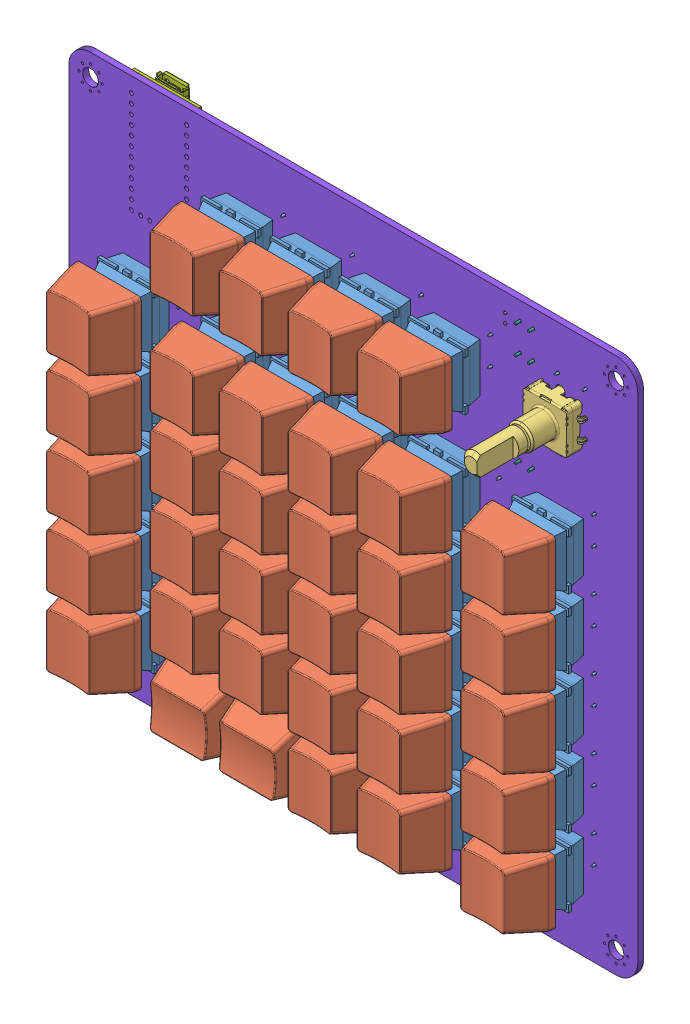
SolidWorks assembly OsseyPad, configuration Default. Lengths in mm.
Overall size (157 148.99 30.28).
224 component instances, 8 part files, 0 mates.
Components (placement in the parent):
- OsseyPad.step-1: OsseyPad.step [Default] at origin size (157 148.99 30.28)
  - mx.step-1: mx.step [Default] at (130.9688 -95.25 7.25) x (-1 0 0) z (0 1 0) size (15.64 22.93 22.24)
    - SOLID.step-1: SOLID.step [Default] at origin size (15.64 22.93 22.24)
  - mxKeycap.step-1: mxKeycap.step [Default] at (121.9688 -86.25 11.95) x (1 0 0) z (0 -1 0) size (18 11.3 18.01)
    - SOLID-0.step-1: SOLID-0.step [Default] at origin size (18 11.3 18.01)
  - mx.step-2: mx.step [Default] at (150.0188 -95.25 7.25) x (-1 0 0) z (0 1 0) size (15.64 22.93 22.24)
    - SOLID.step-1: SOLID.step [Default] at origin size (15.64 22.93 22.24)
  - mxKeycap.step-2: mxKeycap.step [Default] at (141.0188 -86.25 11.95) x (1 0 0) z (0 -1 0) size (18 11.3 18.01)
    - SOLID-0.step-1: SOLID-0.step [Default] at origin size (18 11.3 18.01)
  - mx.step-3: mx.step [Default] at (169.0687 -95.25 7.25) x (-1 0 0) z (0 1 0) size (15.64 22.93 22.24)
    - SOLID.step-1: SOLID.step [Default] at origin size (15.64 22.93 22.24)
  - mxKeycap.step-3: mxKeycap.step [Default] at (160.0688 -86.25 11.95) x (1 0 0) z (0 -1 0) size (18 11.3 18.01)
    - SOLID-0.step-1: SOLID-0.step [Default] at origin size (18 11.3 18.01)
  - mx.step-4: mx.step [Default] at (188.1188 -95.25 7.25) x (-1 0 0) z (0 1 0) size (15.64 22.93 22.24)
    - SOLID.step-1: SOLID.step [Default] at origin size (15.64 22.93 22.24)
  - mxKeycap.step-4: mxKeycap.step [Default] at (179.1188 -86.25 11.95) x (1 0 0) z (0 -1 0) size (18 11.3 18.01)
    - SOLID-0.step-1: SOLID-0.step [Default] at origin size (18 11.3 18.01)
  - mx.step-5: mx.step [Default] at (102.3938 -123.825 7.25) x (-1 0 0) z (0 1 0) size (15.64 22.93 22.24)
    - SOLID.step-1: SOLID.step [Default] at origin size (15.64 22.93 22.24)
  - mxKeycap.step-5: mxKeycap.step [Default] at (93.3937 -114.825 11.95) x (1 0 0) z (0 -1 0) size (18 11.3 18.01)
    - SOLID-0.step-1: SOLID-0.step [Default] at origin size (18 11.3 18.01)
  - mx.step-6: mx.step [Default] at (130.9688 -123.825 7.25) x (-1 0 0) z (0 1 0) size (15.64 22.93 22.24)
    - SOLID.step-1: SOLID.step [Default] at origin size (15.64 22.93 22.24)
  - mxKeycap.step-6: mxKeycap.step [Default] at (121.9688 -114.825 11.95) x (1 0 0) z (0 -1 0) size (18 11.3 18.01)
    - SOLID-0.step-1: SOLID-0.step [Default] at origin size (18 11.3 18.01)
  - mx.step-7: mx.step [Default] at (150.0188 -123.825 7.25) x (-1 0 0) z (0 1 0) size (15.64 22.93 22.24)
    - SOLID.step-1: SOLID.step [Default] at origin size (15.64 22.93 22.24)
  - mxKeycap.step-7: mxKeycap.step [Default] at (141.0188 -114.825 11.95) x (1 0 0) z (0 -1 0) size (18 11.3 18.01)
    - SOLID-0.step-1: SOLID-0.step [Default] at origin size (18 11.3 18.01)
  - mx.step-8: mx.step [Default] at (169.0687 -123.825 7.25) x (-1 0 0) z (0 1 0) size (15.64 22.93 22.24)
    - SOLID.step-1: SOLID.step [Default] at origin size (15.64 22.93 22.24)
  - mxKeycap.step-8: mxKeycap.step [Default] at (160.0688 -114.825 11.95) x (1 0 0) z (0 -1 0) size (18 11.3 18.01)
    - SOLID-0.step-1: SOLID-0.step [Default] at origin size (18 11.3 18.01)
  - mx.step-9: mx.step [Default] at (188.1188 -123.825 7.25) x (-1 0 0) z (0 1 0) size (15.64 22.93 22.24)
    - SOLID.step-1: SOLID.step [Default] at origin size (15.64 22.93 22.24)
  - mxKeycap.step-9: mxKeycap.step [Default] at (179.1188 -114.825 11.95) x (1 0 0) z (0 -1 0) size (18 11.3 18.01)
    - SOLID-0.step-1: SOLID-0.step [Default] at origin size (18 11.3 18.01)
  - mx.step-10: mx.step [Default] at (216.6937 -123.825 7.25) x (-1 0 0) z (0 1 0) size (15.64 22.93 22.24)
    - SOLID.step-1: SOLID.step [Default] at origin size (15.64 22.93 22.24)
  - mxKeycap.step-10: mxKeycap.step [Default] at (207.6938 -114.825 11.95) x (1 0 0) z (0 -1 0) size (18 11.3 18.01)
    - SOLID-0.step-1: SOLID-0.step [Default] at origin size (18 11.3 18.01)
  - mx.step-11: mx.step [Default] at (102.3938 -142.875 7.25) x (-1 0 0) z (0 1 0) size (15.64 22.93 22.24)
    - SOLID.step-1: SOLID.step [Default] at origin size (15.64 22.93 22.24)
  - mxKeycap.step-11: mxKeycap.step [Default] at (93.3937 -133.875 11.95) x (1 0 0) z (0 -1 0) size (18 11.3 18.01)
    - SOLID-0.step-1: SOLID-0.step [Default] at origin size (18 11.3 18.01)
  - mx.step-12: mx.step [Default] at (130.9688 -142.875 7.25) x (-1 0 0) z (0 1 0) size (15.64 22.93 22.24)
    - SOLID.step-1: SOLID.step [Default] at origin size (15.64 22.93 22.24)
  - mxKeycap.step-12: mxKeycap.step [Default] at (121.9688 -133.875 11.95) x (1 0 0) z (0 -1 0) size (18 11.3 18.01)
    - SOLID-0.step-1: SOLID-0.step [Default] at origin size (18 11.3 18.01)
  - mx.step-13: mx.step [Default] at (150.0188 -142.875 7.25) x (-1 0 0) z (0 1 0) size (15.64 22.93 22.24)
    - SOLID.step-1: SOLID.step [Default] at origin size (15.64 22.93 22.24)
  - mxKeycap.step-13: mxKeycap.step [Default] at (141.0188 -133.875 11.95) x (1 0 0) z (0 -1 0) size (18 11.3 18.01)
    - SOLID-0.step-1: SOLID-0.step [Default] at origin size (18 11.3 18.01)
  - mx.step-14: mx.step [Default] at (169.0687 -142.875 7.25) x (-1 0 0) z (0 1 0) size (15.64 22.93 22.24)
    - SOLID.step-1: SOLID.step [Default] at origin size (15.64 22.93 22.24)
  - mxKeycap.step-14: mxKeycap.step [Default] at (160.0688 -133.875 11.95) x (1 0 0) z (0 -1 0) size (18 11.3 18.01)
    - SOLID-0.step-1: SOLID-0.step [Default] at origin size (18 11.3 18.01)
  - mx.step-15: mx.step [Default] at (188.1188 -142.875 7.25) x (-1 0 0) z (0 1 0) size (15.64 22.93 22.24)
    - SOLID.step-1: SOLID.step [Default] at origin size (15.64 22.93 22.24)
  - mxKeycap.step-15: mxKeycap.step [Default] at (179.1188 -133.875 11.95) x (1 0 0) z (0 -1 0) size (18 11.3 18.01)
    - SOLID-0.step-1: SOLID-0.step [Default] at origin size (18 11.3 18.01)
  - mx.step-16: mx.step [Default] at (216.6937 -142.875 7.25) x (-1 0 0) z (0 1 0) size (15.64 22.93 22.24)
    - SOLID.step-1: SOLID.step [Default] at origin size (15.64 22.93 22.24)
  - mxKeycap.step-16: mxKeycap.step [Default] at (207.6938 -133.875 11.95) x (1 0 0) z (0 -1 0) size (18 11.3 18.01)
    - SOLID-0.step-1: SOLID-0.step [Default] at origin size (18 11.3 18.01)
  - mx.step-17: mx.step [Default] at (102.3938 -161.925 7.25) x (-1 0 0) z (0 1 0) size (15.64 22.93 22.24)
    - SOLID.step-1: SOLID.step [Default] at origin size (15.64 22.93 22.24)
  - mxKeycap.step-17: mxKeycap.step [Default] at (93.3937 -152.925 11.95) x (1 0 0) z (0 -1 0) size (18 11.3 18.01)
    - SOLID-0.step-1: SOLID-0.step [Default] at origin size (18 11.3 18.01)
  - mx.step-18: mx.step [Default] at (130.9688 -161.925 7.25) x (-1 0 0) z (0 1 0) size (15.64 22.93 22.24)
    - SOLID.step-1: SOLID.step [Default] at origin size (15.64 22.93 22.24)
  - mxKeycap.step-18: mxKeycap.step [Default] at (121.9688 -152.925 11.95) x (1 0 0) z (0 -1 0) size (18 11.3 18.01)
    - SOLID-0.step-1: SOLID-0.step [Default] at origin size (18 11.3 18.01)
  - mx.step-19: mx.step [Default] at (150.0188 -161.925 7.25) x (-1 0 0) z (0 1 0) size (15.64 22.93 22.24)
    - SOLID.step-1: SOLID.step [Default] at origin size (15.64 22.93 22.24)
  - mxKeycap.step-19: mxKeycap.step [Default] at (141.0188 -152.925 11.95) x (1 0 0) z (0 -1 0) size (18 11.3 18.01)
    - SOLID-0.step-1: SOLID-0.step [Default] at origin size (18 11.3 18.01)
  - mx.step-20: mx.step [Default] at (169.0687 -161.925 7.25) x (-1 0 0) z (0 1 0) size (15.64 22.93 22.24)
    - SOLID.step-1: SOLID.step [Default] at origin size (15.64 22.93 22.24)
  - mxKeycap.step-20: mxKeycap.step [Default] at (160.0688 -152.925 11.95) x (1 0 0) z (0 -1 0) size (18 11.3 18.01)
    - SOLID-0.step-1: SOLID-0.step [Default] at origin size (18 11.3 18.01)
  - mx.step-21: mx.step [Default] at (188.1188 -161.925 7.25) x (-1 0 0) z (0 1 0) size (15.64 22.93 22.24)
    - SOLID.step-1: SOLID.step [Default] at origin size (15.64 22.93 22.24)
  - mxKeycap.step-21: mxKeycap.step [Default] at (179.1188 -152.925 11.95) x (1 0 0) z (0 -1 0) size (18 11.3 18.01)
    - SOLID-0.step-1: SOLID-0.step [Default] at origin size (18 11.3 18.01)
  - mx.step-22: mx.step [Default] at (216.6937 -161.925 7.25) x (-1 0 0) z (0 1 0) size (15.64 22.93 22.24)
    - SOLID.step-1: SOLID.step [Default] at origin size (15.64 22.93 22.24)
  - mxKeycap.step-22: mxKeycap.step [Default] at (207.6938 -152.925 11.95) x (1 0 0) z (0 -1 0) size (18 11.3 18.01)
    - SOLID-0.step-1: SOLID-0.step [Default] at origin size (18 11.3 18.01)
  - mx.step-23: mx.step [Default] at (188.1188 -180.975 7.25) x (-1 0 0) z (0 1 0) size (15.64 22.93 22.24)
    - SOLID.step-1: SOLID.step [Default] at origin size (15.64 22.93 22.24)
  - mxKeycap.step-23: mxKeycap.step [Default] at (179.1188 -171.975 11.95) x (1 0 0) z (0 -1 0) size (18 11.3 18.01)
    - SOLID-0.step-1: SOLID-0.step [Default] at origin size (18 11.3 18.01)
  - mx.step-24: mx.step [Default] at (102.3938 -180.975 7.25) x (-1 0 0) z (0 1 0) size (15.64 22.93 22.24)
    - SOLID.step-1: SOLID.step [Default] at origin size (15.64 22.93 22.24)
  - mxKeycap.step-24: mxKeycap.step [Default] at (93.3937 -171.975 11.95) x (1 0 0) z (0 -1 0) size (18 11.3 18.01)
    - SOLID-0.step-1: SOLID-0.step [Default] at origin size (18 11.3 18.01)
  - mx.step-25: mx.step [Default] at (130.9688 -180.975 7.25) x (-1 0 0) z (0 1 0) size (15.64 22.93 22.24)
    - SOLID.step-1: SOLID.step [Default] at origin size (15.64 22.93 22.24)
  - mxKeycap.step-25: mxKeycap.step [Default] at (121.9688 -171.975 11.95) x (1 0 0) z (0 -1 0) size (18 11.3 18.01)
    - SOLID-0.step-1: SOLID-0.step [Default] at origin size (18 11.3 18.01)
  - mx.step-26: mx.step [Default] at (150.0188 -180.975 7.25) x (-1 0 0) z (0 1 0) size (15.64 22.93 22.24)
    - SOLID.step-1: SOLID.step [Default] at origin size (15.64 22.93 22.24)
  - mxKeycap.step-26: mxKeycap.step [Default] at (141.0188 -171.975 11.95) x (1 0 0) z (0 -1 0) size (18 11.3 18.01)
    - SOLID-0.step-1: SOLID-0.step [Default] at origin size (18 11.3 18.01)
  - mx.step-27: mx.step [Default] at (169.0687 -180.975 7.25) x (-1 0 0) z (0 1 0) size (15.64 22.93 22.24)
    - SOLID.step-1: SOLID.step [Default] at origin size (15.64 22.93 22.24)
  - mxKeycap.step-27: mxKeycap.step [Default] at (160.0688 -171.975 11.95) x (1 0 0) z (0 -1 0) size (18 11.3 18.01)
    - SOLID-0.step-1: SOLID-0.step [Default] at origin size (18 11.3 18.01)
  - mx.step-28: mx.step [Default] at (216.6937 -180.975 7.25) x (-1 0 0) z (0 1 0) size (15.64 22.93 22.24)
    - SOLID.step-1: SOLID.step [Default] at origin size (15.64 22.93 22.24)
  - mxKeycap.step-28: mxKeycap.step [Default] at (207.6938 -171.975 11.95) x (1 0 0) z (0 -1 0) size (18 11.3 18.01)
    - SOLID-0.step-1: SOLID-0.step [Default] at origin size (18 11.3 18.01)
  - mx.step-29: mx.step [Default] at (102.3938 -200.025 7.25) x (-1 0 0) z (0 1 0) size (15.64 22.93 22.24)
    - SOLID.step-1: SOLID.step [Default] at origin size (15.64 22.93 22.24)
  - mxKeycap.step-29: mxKeycap.step [Default] at (93.3937 -191.025 11.95) x (1 0 0) z (0 -1 0) size (18 11.3 18.01)
    - SOLID-0.step-1: SOLID-0.step [Default] at origin size (18 11.3 18.01)
  - mx.step-30: mx.step [Default] at (130.9688 -200.025 7.25) x (0 1 0) z (1 0 0) size (15.64 22.93 22.24)
    - SOLID.step-1: SOLID.step [Default] at origin size (15.64 22.93 22.24)
  - mxKeycap.step-30: mxKeycap.step [Default] at (139.9688 -191.025 11.95) x (0 -1 0) z (-1 0 0) size (18 11.3 18.01)
    - SOLID-0.step-1: SOLID-0.step [Default] at origin size (18 11.3 18.01)
  - mx.step-31: mx.step [Default] at (150.0188 -200.025 7.25) x (0 1 0) z (1 0 0) size (15.64 22.93 22.24)
    - SOLID.step-1: SOLID.step [Default] at origin size (15.64 22.93 22.24)
  - mxKeycap.step-31: mxKeycap.step [Default] at (159.0187 -191.025 11.95) x (0 -1 0) z (-1 0 0) size (18 11.3 18.01)
    - SOLID-0.step-1: SOLID-0.step [Default] at origin size (18 11.3 18.01)
  - mx.step-32: mx.step [Default] at (169.0687 -200.025 7.25) x (-1 0 0) z (0 1 0) size (15.64 22.93 22.24)
    - SOLID.step-1: SOLID.step [Default] at origin size (15.64 22.93 22.24)
  - mxKeycap.step-32: mxKeycap.step [Default] at (160.0688 -191.025 11.95) x (1 0 0) z (0 -1 0) size (18 11.3 18.01)
    - SOLID-0.step-1: SOLID-0.step [Default] at origin size (18 11.3 18.01)
  - mx.step-33: mx.step [Default] at (188.1188 -200.025 7.25) x (-1 0 0) z (0 1 0) size (15.64 22.93 22.24)
    - SOLID.step-1: SOLID.step [Default] at origin size (15.64 22.93 22.24)
  - mxKeycap.step-33: mxKeycap.step [Default] at (179.1188 -191.025 11.95) x (1 0 0) z (0 -1 0) size (18 11.3 18.01)
    - SOLID-0.step-1: SOLID-0.step [Default] at origin size (18 11.3 18.01)
  - mx.step-34: mx.step [Default] at (216.6937 -200.025 7.25) x (-1 0 0) z (0 1 0) size (15.64 22.93 22.24)
    - SOLID.step-1: SOLID.step [Default] at origin size (15.64 22.93 22.24)
  - mxKeycap.step-34: mxKeycap.step [Default] at (207.6938 -191.025 11.95) x (1 0 0) z (0 -1 0) size (18 11.3 18.01)
    - SOLID-0.step-1: SOLID-0.step [Default] at origin size (18 11.3 18.01)
  - EC11E-05SW.step-1: EC11E-05SW.step [Default] at (216.6937 -95 -10.35) x (0 1 0) z (0 0 -1) size (13.28 15.04 28.35)
    - SOLID-1.step-1: SOLID-1.step [Default] at origin size (13.28 15.04 28.35)
  - C_Disc_D3.0mm_W2.0mm_P2.50mm.step-1: C_Disc_D3.0mm_W2.0mm_P2.50mm.step [Default] at (201.53 -111.84 -0.05) x (0 1 0) z (0 0 -1) size (3.35 3.34 5.33)
    - SOLID-2.step-1: SOLID-2.step [Default] at origin size (3.35 3.34 5.33)
  - C_Disc_D3.0mm_W2.0mm_P2.50mm.step-2: C_Disc_D3.0mm_W2.0mm_P2.50mm.step [Default] at (201.53 -78.63 -0.05) x (0 -1 0) z (0 0 -1) size (3.35 3.34 5.33)
    - SOLID-2.step-1: SOLID-2.step [Default] at origin size (3.35 3.34 5.33)
  - D_DO-35_SOD27_P7.62mm_Horizontal.step-1: D_DO-35_SOD27_P7.62mm_Horizontal.step [Default] at (140.4938 -85.725 -0.05) x (0 -1 0) z (0 0 -1) size (8.12 2.93 5.28)
    - COMPOUND.step-1: COMPOUND.step [Default] at origin size (8.12 2.93 5.28)
  - D_DO-35_SOD27_P7.62mm_Horizontal.step-2: D_DO-35_SOD27_P7.62mm_Horizontal.step [Default] at (159.5438 -85.725 -0.05) x (0 -1 0) z (0 0 -1) size (8.12 2.93 5.28)
    - COMPOUND.step-1: COMPOUND.step [Default] at origin size (8.12 2.93 5.28)
  - D_DO-35_SOD27_P7.62mm_Horizontal.step-3: D_DO-35_SOD27_P7.62mm_Horizontal.step [Default] at (178.5938 -85.725 -0.05) x (0 -1 0) z (0 0 -1) size (8.12 2.93 5.28)
    - COMPOUND.step-1: COMPOUND.step [Default] at origin size (8.12 2.93 5.28)
  - D_DO-35_SOD27_P7.62mm_Horizontal.step-4: D_DO-35_SOD27_P7.62mm_Horizontal.step [Default] at (197.6438 -85.725 -0.05) x (0 -1 0) z (0 0 -1) size (8.12 2.93 5.28)
    - COMPOUND.step-1: COMPOUND.step [Default] at origin size (8.12 2.93 5.28)
  - D_DO-35_SOD27_P7.62mm_Horizontal.step-5: D_DO-35_SOD27_P7.62mm_Horizontal.step [Default] at (216.07 -85.725 -0.05) x (1 0 0) z (0 0 -1) size (8.12 2.93 5.28)
    - COMPOUND.step-1: COMPOUND.step [Default] at origin size (8.12 2.93 5.28)
  - D_DO-35_SOD27_P7.62mm_Horizontal.step-6: D_DO-35_SOD27_P7.62mm_Horizontal.step [Default] at (111.9188 -114.3 -0.05) x (0 -1 0) z (0 0 -1) size (8.12 2.93 5.28)
    - COMPOUND.step-1: COMPOUND.step [Default] at origin size (8.12 2.93 5.28)
  - D_DO-35_SOD27_P7.62mm_Horizontal.step-7: D_DO-35_SOD27_P7.62mm_Horizontal.step [Default] at (140.4938 -114.3 -0.05) x (0 -1 0) z (0 0 -1) size (8.12 2.93 5.28)
    - COMPOUND.step-1: COMPOUND.step [Default] at origin size (8.12 2.93 5.28)
  - D_DO-35_SOD27_P7.62mm_Horizontal.step-8: D_DO-35_SOD27_P7.62mm_Horizontal.step [Default] at (159.5438 -114.3 -0.05) x (0 -1 0) z (0 0 -1) size (8.12 2.93 5.28)
    - COMPOUND.step-1: COMPOUND.step [Default] at origin size (8.12 2.93 5.28)
  - D_DO-35_SOD27_P7.62mm_Horizontal.step-9: D_DO-35_SOD27_P7.62mm_Horizontal.step [Default] at (178.5938 -114.3 -0.05) x (0 -1 0) z (0 0 -1) size (8.12 2.93 5.28)
    - COMPOUND.step-1: COMPOUND.step [Default] at origin size (8.12 2.93 5.28)
  - D_DO-35_SOD27_P7.62mm_Horizontal.step-10: D_DO-35_SOD27_P7.62mm_Horizontal.step [Default] at (200.025 -118.78 -0.05) x (0 -1 0) z (0 0 -1) size (8.12 2.93 5.28)
    - COMPOUND.step-1: COMPOUND.step [Default] at origin size (8.12 2.93 5.28)
  - D_DO-35_SOD27_P7.62mm_Horizontal.step-11: D_DO-35_SOD27_P7.62mm_Horizontal.step [Default] at (226.2188 -114.3 -0.05) x (0 -1 0) z (0 0 -1) size (8.12 2.93 5.28)
    - COMPOUND.step-1: COMPOUND.step [Default] at origin size (8.12 2.93 5.28)
  - D_DO-35_SOD27_P7.62mm_Horizontal.step-12: D_DO-35_SOD27_P7.62mm_Horizontal.step [Default] at (111.9188 -133.35 -0.05) x (0 -1 0) z (0 0 -1) size (8.12 2.93 5.28)
    - COMPOUND.step-1: COMPOUND.step [Default] at origin size (8.12 2.93 5.28)
  - D_DO-35_SOD27_P7.62mm_Horizontal.step-13: D_DO-35_SOD27_P7.62mm_Horizontal.step [Default] at (140.4938 -133.35 -0.05) x (0 -1 0) z (0 0 -1) size (8.12 2.93 5.28)
    - COMPOUND.step-1: COMPOUND.step [Default] at origin size (8.12 2.93 5.28)
  - D_DO-35_SOD27_P7.62mm_Horizontal.step-14: D_DO-35_SOD27_P7.62mm_Horizontal.step [Default] at (159.5438 -133.35 -0.05) x (0 -1 0) z (0 0 -1) size (8.12 2.93 5.28)
    - COMPOUND.step-1: COMPOUND.step [Default] at origin size (8.12 2.93 5.28)
  - D_DO-35_SOD27_P7.62mm_Horizontal.step-15: D_DO-35_SOD27_P7.62mm_Horizontal.step [Default] at (163.98 -133.35 -0.05) x (1 0 0) z (0 0 -1) size (8.12 2.93 5.28)
    - COMPOUND.step-1: COMPOUND.step [Default] at origin size (8.12 2.93 5.28)
  - D_DO-35_SOD27_P7.62mm_Horizontal.step-16: D_DO-35_SOD27_P7.62mm_Horizontal.step [Default] at (200.025 -133.35 -0.05) x (0 -1 0) z (0 0 -1) size (8.12 2.93 5.28)
    - COMPOUND.step-1: COMPOUND.step [Default] at origin size (8.12 2.93 5.28)
  - D_DO-35_SOD27_P7.62mm_Horizontal.step-17: D_DO-35_SOD27_P7.62mm_Horizontal.step [Default] at (226.2188 -133.35 -0.05) x (0 -1 0) z (0 0 -1) size (8.12 2.93 5.28)
    - COMPOUND.step-1: COMPOUND.step [Default] at origin size (8.12 2.93 5.28)
  - D_DO-35_SOD27_P7.62mm_Horizontal.step-18: D_DO-35_SOD27_P7.62mm_Horizontal.step [Default] at (111.9188 -152.4 -0.05) x (0 -1 0) z (0 0 -1) size (8.12 2.93 5.28)
    - COMPOUND.step-1: COMPOUND.step [Default] at origin size (8.12 2.93 5.28)
  - D_DO-35_SOD27_P7.62mm_Horizontal.step-19: D_DO-35_SOD27_P7.62mm_Horizontal.step [Default] at (140.4938 -152.4 -0.05) x (0 -1 0) z (0 0 -1) size (8.12 2.93 5.28)
    - COMPOUND.step-1: COMPOUND.step [Default] at origin size (8.12 2.93 5.28)
  - D_DO-35_SOD27_P7.62mm_Horizontal.step-20: D_DO-35_SOD27_P7.62mm_Horizontal.step [Default] at (159.5438 -152.4 -0.05) x (0 -1 0) z (0 0 -1) size (8.12 2.93 5.28)
    - COMPOUND.step-1: COMPOUND.step [Default] at origin size (8.12 2.93 5.28)
  - D_DO-35_SOD27_P7.62mm_Horizontal.step-21: D_DO-35_SOD27_P7.62mm_Horizontal.step [Default] at (178.5938 -152.4 -0.05) x (0 -1 0) z (0 0 -1) size (8.12 2.93 5.28)
    - COMPOUND.step-1: COMPOUND.step [Default] at origin size (8.12 2.93 5.28)
  - D_DO-35_SOD27_P7.62mm_Horizontal.step-22: D_DO-35_SOD27_P7.62mm_Horizontal.step [Default] at (200.025 -152.4 -0.05) x (0 -1 0) z (0 0 -1) size (8.12 2.93 5.28)
    - COMPOUND.step-1: COMPOUND.step [Default] at origin size (8.12 2.93 5.28)
  - D_DO-35_SOD27_P7.62mm_Horizontal.step-23: D_DO-35_SOD27_P7.62mm_Horizontal.step [Default] at (226.2188 -152.4 -0.05) x (0 -1 0) z (0 0 -1) size (8.12 2.93 5.28)
    - COMPOUND.step-1: COMPOUND.step [Default] at origin size (8.12 2.93 5.28)
  - D_DO-35_SOD27_P7.62mm_Horizontal.step-24: D_DO-35_SOD27_P7.62mm_Horizontal.step [Default] at (200.025 -171.45 -0.05) x (0 -1 0) z (0 0 -1) size (8.12 2.93 5.28)
    - COMPOUND.step-1: COMPOUND.step [Default] at origin size (8.12 2.93 5.28)
  - D_DO-35_SOD27_P7.62mm_Horizontal.step-25: D_DO-35_SOD27_P7.62mm_Horizontal.step [Default] at (111.9188 -171.45 -0.05) x (0 -1 0) z (0 0 -1) size (8.12 2.93 5.28)
    - COMPOUND.step-1: COMPOUND.step [Default] at origin size (8.12 2.93 5.28)
  - D_DO-35_SOD27_P7.62mm_Horizontal.step-26: D_DO-35_SOD27_P7.62mm_Horizontal.step [Default] at (140.4938 -171.45 -0.05) x (0 -1 0) z (0 0 -1) size (8.12 2.93 5.28)
    - COMPOUND.step-1: COMPOUND.step [Default] at origin size (8.12 2.93 5.28)
  - D_DO-35_SOD27_P7.62mm_Horizontal.step-27: D_DO-35_SOD27_P7.62mm_Horizontal.step [Default] at (159.5438 -171.45 -0.05) x (0 -1 0) z (0 0 -1) size (8.12 2.93 5.28)
    - COMPOUND.step-1: COMPOUND.step [Default] at origin size (8.12 2.93 5.28)
  - D_DO-35_SOD27_P7.62mm_Horizontal.step-28: D_DO-35_SOD27_P7.62mm_Horizontal.step [Default] at (226.2188 -171.45 -0.05) x (0 -1 0) z (0 0 -1) size (8.12 2.93 5.28)
    - COMPOUND.step-1: COMPOUND.step [Default] at origin size (8.12 2.93 5.28)
  - D_DO-35_SOD27_P7.62mm_Horizontal.step-29: D_DO-35_SOD27_P7.62mm_Horizontal.step [Default] at (111.9188 -190.5 -0.05) x (0 -1 0) z (0 0 -1) size (8.12 2.93 5.28)
    - COMPOUND.step-1: COMPOUND.step [Default] at origin size (8.12 2.93 5.28)
  - D_DO-35_SOD27_P7.62mm_Horizontal.step-30: D_DO-35_SOD27_P7.62mm_Horizontal.step [Default] at (140.5 -188.125 -0.05) x (0 -1 0) z (0 0 -1) size (8.12 2.93 5.28)
    - COMPOUND.step-1: COMPOUND.step [Default] at origin size (8.12 2.93 5.28)
  - D_DO-35_SOD27_P7.62mm_Horizontal.step-31: D_DO-35_SOD27_P7.62mm_Horizontal.step [Default] at (159.5438 -190.5 -0.05) x (0 -1 0) z (0 0 -1) size (8.12 2.93 5.28)
    - COMPOUND.step-1: COMPOUND.step [Default] at origin size (8.12 2.93 5.28)
  - D_DO-35_SOD27_P7.62mm_Horizontal.step-32: D_DO-35_SOD27_P7.62mm_Horizontal.step [Default] at (178.5938 -190.5 -0.05) x (0 -1 0) z (0 0 -1) size (8.12 2.93 5.28)
    - COMPOUND.step-1: COMPOUND.step [Default] at origin size (8.12 2.93 5.28)
  - D_DO-35_SOD27_P7.62mm_Horizontal.step-33: D_DO-35_SOD27_P7.62mm_Horizontal.step [Default] at (200.025 -190.5 -0.05) x (0 -1 0) z (0 0 -1) size (8.12 2.93 5.28)
    - COMPOUND.step-1: COMPOUND.step [Default] at origin size (8.12 2.93 5.28)
  - D_DO-35_SOD27_P7.62mm_Horizontal.step-34: D_DO-35_SOD27_P7.62mm_Horizontal.step [Default] at (226.2188 -190.5 -0.05) x (0 -1 0) z (0 0 -1) size (8.12 2.93 5.28)
    - COMPOUND.step-1: COMPOUND.step [Default] at origin size (8.12 2.93 5.28)
  - R_Axial_DIN0207_L6.3mm_D2.5mm_P7.62mm_Horizontal.step-1: R_Axial_DIN0207_L6.3mm_D2.5mm_P7.62mm_Horizontal.step [Default] at (209.19 -78.58 -0.05) x (0 -1 0) z (0 0 -1) size (8.22 3.43 5.84)
    - SOLID-3.step-1: SOLID-3.step [Default] at origin size (8.22 3.43 5.84)
  - R_Axial_DIN0207_L6.3mm_D2.5mm_P7.62mm_Horizontal.step-2: R_Axial_DIN0207_L6.3mm_D2.5mm_P7.62mm_Horizontal.step [Default] at (209.17 -111.92 -0.05) x (0 1 0) z (0 0 -1) size (8.22 3.43 5.84)
    - SOLID-3.step-1: SOLID-3.step [Default] at origin size (8.22 3.43 5.84)
  - R_Axial_DIN0207_L6.3mm_D2.5mm_P7.62mm_Horizontal.step-3: R_Axial_DIN0207_L6.3mm_D2.5mm_P7.62mm_Horizontal.step [Default] at (205.53 -86.21 -0.05) x (0 1 0) z (0 0 -1) size (8.22 3.43 5.84)
    - SOLID-3.step-1: SOLID-3.step [Default] at origin size (8.22 3.43 5.84)
  - R_Axial_DIN0207_L6.3mm_D2.5mm_P7.62mm_Horizontal.step-4: R_Axial_DIN0207_L6.3mm_D2.5mm_P7.62mm_Horizontal.step [Default] at (205.53 -104.3 -0.05) x (0 -1 0) z (0 0 -1) size (8.22 3.43 5.84)
    - SOLID-3.step-1: SOLID-3.step [Default] at origin size (8.22 3.43 5.84)
  - D_DO-35_SOD27_P7.62mm_Horizontal.step-35: D_DO-35_SOD27_P7.62mm_Horizontal.step [Default] at (163.98 -171.45 -0.05) x (1 0 0) z (0 0 -1) size (8.12 2.93 5.28)
    - COMPOUND.step-1: COMPOUND.step [Default] at origin size (8.12 2.93 5.28)
  - Arduino_Pro_Micro_Sparkfun.step-1: Arduino_Pro_Micro_Sparkfun.step [Default] at (96.673 -73.7095 -0.05) x (1 0 0) z (0 1 0) size (18.4 4.45 34.27)
    - COMPOUND-4.step-1: COMPOUND-4.step [Default] at origin size (18.4 4.45 34.27)
  - COMPOUND-5.step-1: COMPOUND-5.step [Default] at origin size (157 148 1.6)
